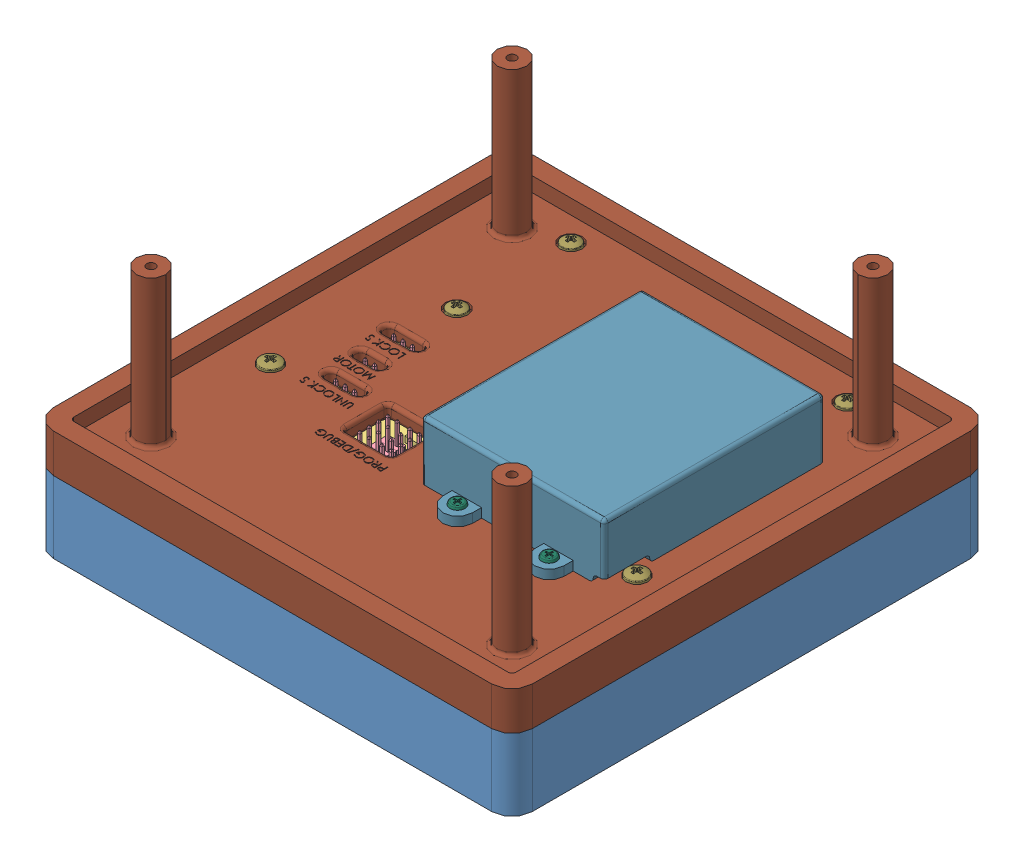
SolidWorks assembly Housing ASSY TOP, configuration Default. Lengths in mm.
Overall size (130 68.9 130).
81 component instances, 15 part files, 42 mates.
Components (placement in the parent):
- Housing-Top-1: Housing-Top [Default] at (0.5206 130 -0.9544) size (130 20 130)
- LCD cover-1: LCD cover [Default] at (0.5206 132.5 -38.9544) size (83 2.5 39)
- PCB ASSY-2: PCB ASSY [Default] at (-38.2241 57.9274 36.8538) x (1 0 0) z (0 1 0) size (111.4 79.3 20.98)
  - pcb-1: pcb [Default] at (-55.2553 -31.6918 89.0126) size (111.4 79.3 4.54)
  - pin header double row- 20 contacts-2: pin header double row- 20 contacts [Default] at (31.3735 92.5733 87.6126) x (1 0 0) z (0 1 0) size (2.54 11.54 2.54)
  - pin header double row- 20 contacts-28: pin header double row- 20 contacts [Default] at (33.9135 92.5733 87.6126) x (1 0 0) z (0 1 0) size (2.54 11.54 2.54)
  - pin header double row- 20 contacts-29: pin header double row- 20 contacts [Default] at (36.4535 92.5733 87.6126) x (1 0 0) z (0 1 0) size (2.54 11.54 2.54)
  - pin header double row- 20 contacts-30: pin header double row- 20 contacts [Default] at (38.9935 92.5733 87.6126) x (1 0 0) z (0 1 0) size (2.54 11.54 2.54)
  - pin header double row- 20 contacts-31: pin header double row- 20 contacts [Default] at (41.5335 92.5733 87.6126) x (1 0 0) z (0 1 0) size (2.54 11.54 2.54)
  - pin header double row- 20 contacts-32: pin header double row- 20 contacts [Default] at (44.0735 92.5733 87.6126) x (1 0 0) z (0 1 0) size (2.54 11.54 2.54)
  - pin header double row- 20 contacts-33: pin header double row- 20 contacts [Default] at (46.6135 92.5733 87.6126) x (1 0 0) z (0 1 0) size (2.54 11.54 2.54)
  - pin header double row- 20 contacts-34: pin header double row- 20 contacts [Default] at (49.1535 92.5733 87.6126) x (1 0 0) z (0 1 0) size (2.54 11.54 2.54)
  - pin header double row- 20 contacts-35: pin header double row- 20 contacts [Default] at (51.6935 92.5733 87.6126) x (1 0 0) z (0 1 0) size (2.54 11.54 2.54)
  - pin header double row- 20 contacts-36: pin header double row- 20 contacts [Default] at (54.2335 92.5733 87.6126) x (1 0 0) z (0 1 0) size (2.54 11.54 2.54)
  - pin header double row- 20 contacts-37: pin header double row- 20 contacts [Default] at (56.7735 92.5733 87.6126) x (1 0 0) z (0 1 0) size (2.54 11.54 2.54)
  - pin header double row- 20 contacts-38: pin header double row- 20 contacts [Default] at (59.3135 92.5733 87.6126) x (1 0 0) z (0 1 0) size (2.54 11.54 2.54)
  - pin header double row- 20 contacts-39: pin header double row- 20 contacts [Default] at (61.8535 92.5733 87.6126) x (1 0 0) z (0 1 0) size (2.54 11.54 2.54)
  - pin header double row- 20 contacts-40: pin header double row- 20 contacts [Default] at (64.3935 92.5733 87.6126) x (1 0 0) z (0 1 0) size (2.54 11.54 2.54)
  - pin header double row- 20 contacts-41: pin header double row- 20 contacts [Default] at (66.9335 92.5733 87.6126) x (1 0 0) z (0 1 0) size (2.54 11.54 2.54)
  - pin header double row- 20 contacts-42: pin header double row- 20 contacts [Default] at (69.4735 92.5733 87.6126) x (1 0 0) z (0 1 0) size (2.54 11.54 2.54)
  - pj-072c-smt-1: pj-072c-smt [Default] at (85.4947 95.3082 91.3126) x (-1 0 0) z (0 1 0) size (5.8 5.75 10.4)
    - pj-072c-smt_01-1: pj-072c-smt_01 [Default] at origin size (5.8 5.75 3.2)
    - pj-072c-smt_02-1: pj-072c-smt_02 [Default] at origin size (1.2 3 3.2)
    - pj-072c-smt_03-1: pj-072c-smt_03 [Default] at origin size (1.45 4.4 3.2)
    - pj-072c-smt_04-1: pj-072c-smt_04 [Default] at origin size (5.7 5.75 9.6)
  - LCD spacer-1: LCD spacer [Default] at (76.2447 91.3082 87.6126) x (0 1 0) z (-1 0 0) size (5 2.54 5)
  - LCD spacer-2: LCD spacer [Default] at (76.2447 60.3082 85.0726) x (1 0 0) z (0 -1 0) size (5 2.54 5)
  - LCD spacer-3: LCD spacer [Default] at (1.2447 60.3082 85.0726) x (1 0 0) z (0 -1 0) size (5 2.54 5)
  - LCD spacer-4: LCD spacer [Default] at (1.2447 91.3082 85.0726) x (1 0 0) z (0 -1 0) size (5 2.54 5)
  - 16x2 Lcd display dsgn arch 2016-edit-00-1: 16x2 Lcd display dsgn arch 2016-edit-00 [Default] at (38.7447 75.8082 83.5726) x (1 0 0) z (0 0 -1) size (80 36 8.5)
  - pin header double row- 20 contacts-43: pin header double row- 20 contacts [Default] at (45.0911 54.5782 87.6126) x (1 0 0) z (0 1 0) size (2.54 11.54 2.54)
  - pin header double row- 20 contacts-44: pin header double row- 20 contacts [Default] at (42.5511 54.5782 87.6126) x (1 0 0) z (0 1 0) size (2.54 11.54 2.54)
  - pin header double row- 20 contacts-45: pin header double row- 20 contacts [Default] at (40.0111 54.5782 87.6126) x (1 0 0) z (0 1 0) size (2.54 11.54 2.54)
  - pin header double row- 20 contacts-46: pin header double row- 20 contacts [Default] at (37.4711 54.5782 87.6126) x (1 0 0) z (0 1 0) size (2.54 11.54 2.54)
  - pin header double row- 20 contacts-47: pin header double row- 20 contacts [Default] at (34.9311 54.5782 87.6126) x (1 0 0) z (0 1 0) size (2.54 11.54 2.54)
  - pin header double row- 20 contacts-48: pin header double row- 20 contacts [Default] at (32.3911 54.5782 87.6126) x (1 0 0) z (0 1 0) size (2.54 11.54 2.54)
  - pin header double row- 20 contacts-49: pin header double row- 20 contacts [Default] at (29.8511 54.5782 87.6126) x (1 0 0) z (0 1 0) size (2.54 11.54 2.54)
  - pin header double row- 20 contacts-50: pin header double row- 20 contacts [Default] at (-3.1653 45.0418 89.0126) x (1 0 0) z (0 -1 0) size (2.54 11.54 2.54)
  - pin header double row- 20 contacts-51: pin header double row- 20 contacts [Default] at (-1.3422 35.5094 89.0126) x (1 0 0) z (0 -1 0) size (2.54 11.54 2.54)
  - pin header double row- 20 contacts-52: pin header double row- 20 contacts [Default] at (-0.4792 26.6283 89.0126) x (1 0 0) z (0 -1 0) size (2.54 11.54 2.54)
  - pin header double row- 20 contacts-53: pin header double row- 20 contacts [Default] at (17.5747 25.2818 89.0126) x (1 0 0) z (0 -1 0) size (2.54 11.54 2.54)
  - pin header double row- 20 contacts-54: pin header double row- 20 contacts [Default] at (21.0383 25.2782 89.0126) x (1 0 0) z (0 -1 0) size (2.54 11.54 2.54)
  - pin header double row- 20 contacts-55: pin header double row- 20 contacts [Default] at (-0.6253 45.0418 89.0126) x (1 0 0) z (0 -1 0) size (2.54 11.54 2.54)
  - pin header double row- 20 contacts-56: pin header double row- 20 contacts [Default] at (1.9147 45.0418 89.0126) x (1 0 0) z (0 -1 0) size (2.54 11.54 2.54)
  - pin header double row- 20 contacts-57: pin header double row- 20 contacts [Default] at (1.1978 35.5094 89.0126) x (1 0 0) z (0 -1 0) size (2.54 11.54 2.54)
  - pin header double row- 20 contacts-58: pin header double row- 20 contacts [Default] at (2.0608 26.6283 89.0126) x (1 0 0) z (0 -1 0) size (2.54 11.54 2.54)
  - pin header double row- 20 contacts-59: pin header double row- 20 contacts [Default] at (4.6008 26.6283 89.0126) x (1 0 0) z (0 -1 0) size (2.54 11.54 2.54)
  - pin header double row- 20 contacts-60: pin header double row- 20 contacts [Default] at (23.5783 25.2782 89.0126) x (1 0 0) z (0 -1 0) size (2.54 11.54 2.54)
  - pin header double row- 20 contacts-61: pin header double row- 20 contacts [Default] at (21.0383 22.7382 89.0126) x (1 0 0) z (0 -1 0) size (2.54 11.54 2.54)
  - pin header double row- 20 contacts-62: pin header double row- 20 contacts [Default] at (23.5783 22.7382 89.0126) x (1 0 0) z (0 -1 0) size (2.54 11.54 2.54)
  - pin header double row- 20 contacts-63: pin header double row- 20 contacts [Default] at (21.0383 20.1982 89.0126) x (1 0 0) z (0 -1 0) size (2.54 11.54 2.54)
  - pin header double row- 20 contacts-64: pin header double row- 20 contacts [Default] at (23.5783 20.1982 89.0126) x (1 0 0) z (0 -1 0) size (2.54 11.54 2.54)
  - pin header double row- 20 contacts-65: pin header double row- 20 contacts [Default] at (21.0383 17.6582 89.0126) x (1 0 0) z (0 -1 0) size (2.54 11.54 2.54)
  - pin header double row- 20 contacts-66: pin header double row- 20 contacts [Default] at (23.5783 17.6582 89.0126) x (1 0 0) z (0 -1 0) size (2.54 11.54 2.54)
  - pin header double row- 20 contacts-67: pin header double row- 20 contacts [Default] at (15.0347 25.2818 89.0126) x (1 0 0) z (0 -1 0) size (2.54 11.54 2.54)
  - pin header double row- 20 contacts-68: pin header double row- 20 contacts [Default] at (17.5747 22.7418 89.0126) x (1 0 0) z (0 -1 0) size (2.54 11.54 2.54)
  - pin header double row- 20 contacts-69: pin header double row- 20 contacts [Default] at (15.0347 22.7418 89.0126) x (1 0 0) z (0 -1 0) size (2.54 11.54 2.54)
  - pin header double row- 20 contacts-70: pin header double row- 20 contacts [Default] at (17.5747 20.2018 89.0126) x (1 0 0) z (0 -1 0) size (2.54 11.54 2.54)
  - pin header double row- 20 contacts-71: pin header double row- 20 contacts [Default] at (15.0347 20.2018 89.0126) x (1 0 0) z (0 -1 0) size (2.54 11.54 2.54)
  - pin header double row- 20 contacts-72: pin header double row- 20 contacts [Default] at (17.5747 17.6618 89.0126) x (1 0 0) z (0 -1 0) size (2.54 11.54 2.54)
  - pin header double row- 20 contacts-73: pin header double row- 20 contacts [Default] at (15.0347 17.6618 89.0126) x (1 0 0) z (0 -1 0) size (2.54 11.54 2.54)
  - pin header double row- 20 contacts-74: pin header double row- 20 contacts [Default] at (78.3029 68.2428 89.0126) x (1 0 0) z (0 -1 0) size (2.54 11.54 2.54)
  - pin header double row- 20 contacts-75: pin header double row- 20 contacts [Default] at (75.7629 68.2428 89.0126) x (1 0 0) z (0 -1 0) size (2.54 11.54 2.54)
  - pin header double row- 20 contacts-76: pin header double row- 20 contacts [Default] at (73.2229 68.2428 89.0126) x (1 0 0) z (0 -1 0) size (2.54 11.54 2.54)
- Housing-Middle-1: Housing-Middle [Default] at (0.5206 160 -0.9544) x (-1 0 0) z (0 0 1) size (130 49 130)
- pan head cross recess screw_din-3: pan head cross recess screw_din [DIN EN ISO 7045 - M2.5 x 16 - Z - 16S] at (38.0206 157.1 -23.4544) x (0 -1 0) z (0 0 1) size (18.05 5 5)
- pan head cross recess screw_din-4: pan head cross recess screw_din [DIN EN ISO 7045 - M2.5 x 16 - Z - 16S] at (-36.9794 157.1 -54.4544) x (0 -1 0) z (0 0 1) size (18.05 5 5)
- pan head cross recess screw_din-5: pan head cross recess screw_din [DIN EN ISO 7045 - M2.5 x 16 - Z - 16S] at (38.0206 157.1 -54.4544) x (0 -1 0) z (0 0 1) size (18.05 5 5)
- pan head cross recess screw_din-6: pan head cross recess screw_din [DIN EN ISO 7045 - M2.5 x 16 - Z - 16S] at (-36.9794 157.1 -23.4544) x (0 -1 0) z (0 0 1) size (18.05 5 5)
- pan head cross recess screw_din-12: pan head cross recess screw_din [DIN EN ISO 7045 - M3 x 12 - Z - 12S] at (-49.2794 157.4 14.8456) x (0 -1 0) z (0 0 1) size (14.35 5.6 5.6)
- pan head cross recess screw_din-13: pan head cross recess screw_din [DIN EN ISO 7045 - M3 x 12 - Z - 12S] at (50.2206 157.4 14.8456) x (0 -1 0) z (0 0 1) size (14.35 5.6 5.6)
- Keypad 3x4-2: Keypad 3x4 [Default] at (0.5206 138.1 17.7769) x (-1 0 0) z (0 0 1) size (51 11 64)
- pan head cross recess screw_din-15: pan head cross recess screw_din [DIN EN ISO 7045 - M2.2 x 6 - Z - 6S] at (23.5206 139.7 -11.7231) x (0 -1 0) z (0 0 1) size (7.57 4 4)
- pan head cross recess screw_din-16: pan head cross recess screw_din [DIN EN ISO 7045 - M2.2 x 6 - Z - 6S] at (-22.4794 139.7 47.2769) x (0 -1 0) z (0 0 1) size (7.57 4 4)
- pan head cross recess screw_din-17: pan head cross recess screw_din [DIN EN ISO 7045 - M2.2 x 6 - Z - 6S] at (23.5206 139.7 47.2769) x (0 -1 0) z (0 0 1) size (7.57 4 4)
- pan head cross recess screw_din-18: pan head cross recess screw_din [DIN EN ISO 7045 - M2.2 x 6 - Z - 6S] at (-22.4794 139.7 -11.7231) x (0 -1 0) z (0 0 1) size (7.57 4 4)
- Battery holder-2: Battery holder [Default] at (24.0822 172 -7.5089) x (-1 0 0) z (0 0 1) size (49.75 16 72.89)
- SNZS-M2_5-6-1: SNZS-M2_5-6 [Default] at (36.5206 158.5 -39.9544) x (0 -1 0) z (0 0 1) size (6.8 4 4)
- SNZS-M2_5-6-2: SNZS-M2_5-6 [Default] at (36.5206 158.5 24.9456) x (0 -1 0) z (0 0 1) size (6.8 4 4)
- SNZS-M2_5-6-3: SNZS-M2_5-6 [Default] at (11.6206 158.5 24.9456) x (0 -1 0) z (0 0 1) size (6.8 4 4)
- SNZS-M2_5-6-4: SNZS-M2_5-6 [Default] at (11.6206 158.5 -39.9544) x (0 -1 0) z (0 0 1) size (6.8 4 4)
Mates (geometry in assembly coordinates):
- Concentric1: concentric aligned: cylinder of Housing-Top-1 through (38.0206 141.5 -54.4544) axis (0 -1 0) radius 3; cylinder of LCD cover-1 through (38.0206 135 -54.4544) axis (0 -1 0) radius 3.5
- Coincident2: coincident anti-aligned: plane of Housing-Top-1 through (0.5206 132.5 -0.9544) normal (0 1 0); plane of LCD cover-1 through (0.5206 132.5 -38.9544) normal (0 -1 0)
- Coincident3: coincident anti-aligned: plane of Housing-Top-1 through (38.0206 141.5 -54.4544) normal (0 1 0); plane of PCB ASSY-2/16x2 Lcd display dsgn arch 2016-edit-00-1 through (0.5206 141.5 -38.9544) normal (0 -1 0)
- Parallel1: parallel anti-aligned: plane of Housing-Top-1 through (-18.4794 130 46.5456) normal (0 0 -1); plane of ? through (19.7706 129.6 45.5543) normal (0 0 1)
- Distance1: distance = 0.5 mm anti-aligned: plane of ? through (-22.2294 129.6 41.5543) normal (-1 0 0); plane of Housing-Top-1 through (-22.7294 130 -6.7044) normal (1 0 0)
- Coincident9: coincident anti-aligned: plane of Housing-Top-1 through (0.5206 135 -0.9544) normal (0 1 0); plane of ? through (0.7706 135 17.5543) normal (0 -1 0)
- Coincident16: coincident anti-aligned: plane of Housing-Top-1 through (-58.9794 149.5 58.5456) normal (0 1 0); plane of Housing-Middle-1 through (60.0206 149.5 -60.4544) normal (0 -1 0)
- Coincident17: coincident aligned: plane of Housing-Top-1 through (65.5206 150 58.5456) normal (1 0 0); plane of Housing-Middle-1 through (65.5206 150 -60.4544) normal (1 0 0)
- Coincident18: coincident aligned: plane of Housing-Top-1 through (-58.9794 150 -65.9544) normal (0 0 -1); plane of Housing-Middle-1 through (-58.9794 150 -65.9544) normal (0 0 -1)
- Concentric4: concentric anti-aligned: circle of Housing-Middle-1; cylinder of pan head cross recess screw_din-3 through (38.0206 182.5 -23.4544) axis (0 1 0) radius 1.25
- Coincident21: coincident aligned: plane of Housing-Middle-1 through (38.0206 155 -23.4544) normal (0 1 0); circle of pan head cross recess screw_din-3
- Concentric5: concentric anti-aligned: circle of Housing-Middle-1; cylinder of pan head cross recess screw_din-5 through (38.0206 182.5 -54.4544) axis (0 1 0) radius 1.25
- Coincident23: coincident anti-aligned: plane of Housing-Middle-1 through (38.0206 155 -54.4544) normal (0 1 0); plane of pan head cross recess screw_din-5 through (39.2706 155 -54.4544) normal (0 -1 0)
- Concentric6: concentric anti-aligned: circle of Housing-Middle-1; cylinder of pan head cross recess screw_din-4 through (-36.9794 182.5 -54.4544) axis (0 1 0) radius 1.25
- Coincident25: coincident anti-aligned: plane of Housing-Middle-1 through (-36.9794 155 -54.4544) normal (0 1 0); plane of pan head cross recess screw_din-4 through (-35.7294 155 -54.4544) normal (0 -1 0)
- Concentric7: concentric anti-aligned: circle of Housing-Middle-1; cylinder of pan head cross recess screw_din-6 through (-36.9794 182.5 -23.4544) axis (0 1 0) radius 1.25
- Coincident27: coincident anti-aligned: plane of Housing-Middle-1 through (-36.9794 155 -23.4544) normal (0 1 0); plane of pan head cross recess screw_din-6 through (-35.7294 155 -23.4544) normal (0 -1 0)
- Concentric8: concentric anti-aligned: circle of Housing-Middle-1; cylinder of pan head cross recess screw_din-12 through (-49.2794 182.8 14.8456) axis (0 1 0) radius 1.5
- Coincident28: coincident anti-aligned: plane of Housing-Middle-1 through (-49.2794 155 14.8456) normal (0 1 0); plane of pan head cross recess screw_din-12 through (-47.7794 155 14.8456) normal (0 -1 0)
- Concentric9: concentric anti-aligned: circle of Housing-Middle-1; cylinder of pan head cross recess screw_din-13 through (50.2206 182.8 14.8456) axis (0 1 0) radius 1.5
- Coincident29: coincident anti-aligned: plane of Housing-Middle-1 through (50.2206 155 14.8456) normal (0 1 0); plane of pan head cross recess screw_din-13 through (51.7206 155 14.8456) normal (0 -1 0)
- Concentric10: concentric anti-aligned: circle of Housing-Top-1; circle of Keypad 3x4-2
- Concentric11: concentric anti-aligned: circle of Housing-Top-1; circle of Keypad 3x4-2
- Coincident30: coincident anti-aligned: plane of Housing-Top-1 through (0.5206 135 -0.9544) normal (0 1 0); plane of Keypad 3x4-2 through (0.5206 135 17.7769) normal (0 -1 0)
- Concentric12: concentric anti-aligned: circle of Keypad 3x4-2; cylinder of pan head cross recess screw_din-18 through (-22.4794 165.1 -11.7231) axis (0 1 0) radius 1
- Coincident31: coincident anti-aligned: plane of Keypad 3x4-2 through (0.5206 138.1 17.7769) normal (0 1 0); plane of pan head cross recess screw_din-18 through (-21.4794 138.1 -11.7231) normal (0 -1 0)
- Concentric13: concentric anti-aligned: circle of Keypad 3x4-2; cylinder of pan head cross recess screw_din-15 through (23.5206 165.1 -11.7231) axis (0 1 0) radius 1
- Coincident32: coincident anti-aligned: plane of Keypad 3x4-2 through (0.5206 138.1 17.7769) normal (0 1 0); plane of pan head cross recess screw_din-15 through (24.5206 138.1 -11.7231) normal (0 -1 0)
- Concentric14: concentric anti-aligned: circle of Keypad 3x4-2; cylinder of pan head cross recess screw_din-17 through (23.5206 165.1 47.2769) axis (0 1 0) radius 1
- Coincident33: coincident anti-aligned: plane of Keypad 3x4-2 through (0.5206 138.1 17.7769) normal (0 1 0); plane of pan head cross recess screw_din-17 through (24.5206 138.1 47.2769) normal (0 -1 0)
- Concentric15: concentric anti-aligned: circle of Keypad 3x4-2; cylinder of pan head cross recess screw_din-16 through (-22.4794 165.1 47.2769) axis (0 1 0) radius 1
- Coincident34: coincident anti-aligned: plane of Keypad 3x4-2 through (0.5206 138.1 17.7769) normal (0 1 0); plane of pan head cross recess screw_din-16 through (-21.4794 138.1 47.2769) normal (0 -1 0)
- Concentric16: concentric anti-aligned: circle of Housing-Middle-1; circle of Battery holder-2
- Coincident35: coincident anti-aligned: plane of Housing-Middle-1 through (0.5206 156 -0.9544) normal (0 1 0); plane of Battery holder-2 through (24.0822 156 -7.5089) normal (0 -1 0)
- Concentric18: concentric aligned: circle of Housing-Middle-1; circle of SNZS-M2_5-6-4
- Concentric19: concentric aligned: circle of Housing-Middle-1; circle of SNZS-M2_5-6-1
- Concentric20: concentric aligned: circle of Housing-Middle-1; circle of SNZS-M2_5-6-3
- Concentric21: concentric aligned: circle of Housing-Middle-1; circle of SNZS-M2_5-6-2
- Coincident38: coincident anti-aligned: plane of Battery holder-2 through (11.6438 158.5 24.9366) normal (0 1 0); plane of SNZS-M2_5-6-3 through (13.6206 158.5 24.9456) normal (0 -1 0)
- Coincident39: coincident anti-aligned: plane of Battery holder-2 through (36.5206 158.5 24.9366) normal (0 1 0); plane of SNZS-M2_5-6-2 through (38.5206 158.5 24.9456) normal (0 -1 0)
- Coincident40: coincident anti-aligned: plane of Battery holder-2 through (36.5206 158.5 -39.9544) normal (0 1 0); plane of SNZS-M2_5-6-1 through (38.5206 158.5 -39.9544) normal (0 -1 0)
- Coincident41: coincident anti-aligned: plane of Battery holder-2 through (11.6438 158.5 -39.9544) normal (0 1 0); plane of SNZS-M2_5-6-4 through (13.6206 158.5 -39.9544) normal (0 -1 0)
